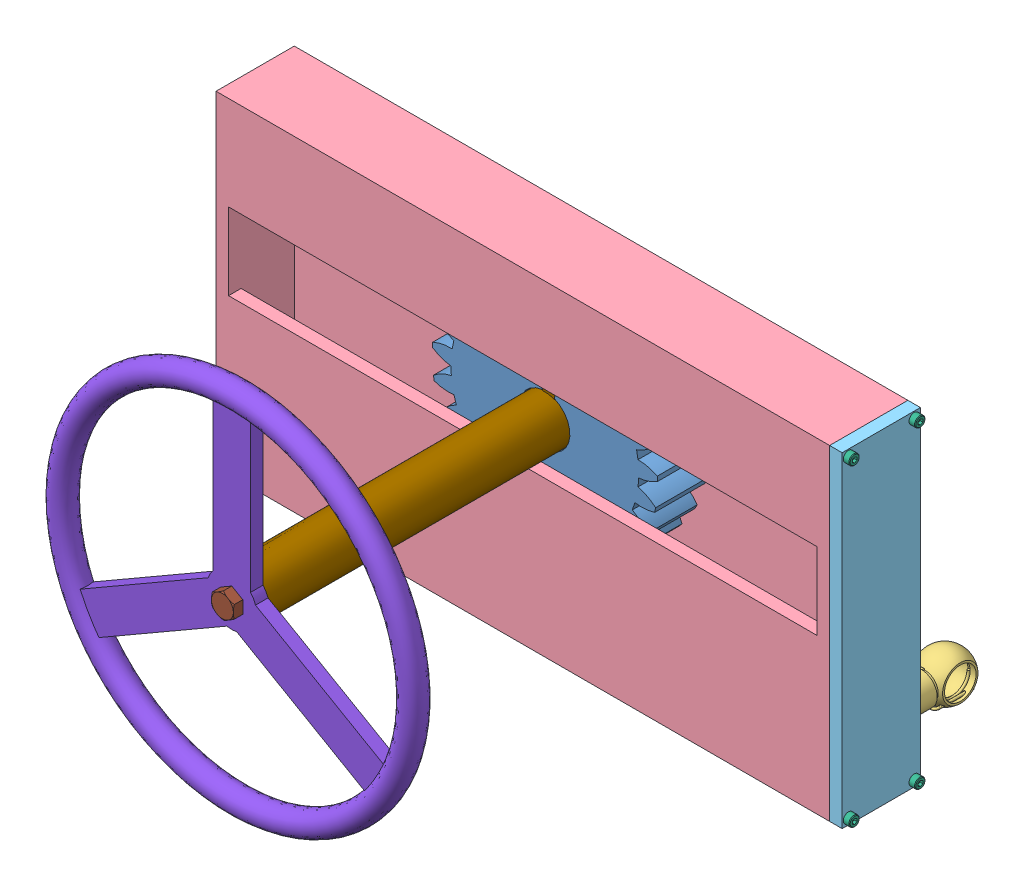
SolidWorks assembly STA1, configuration Default. Lengths in mm.
Overall size (320.68 259.28 240.21).
16 component instances, 11 part files, 39 mates.
Components (placement in the parent):
- STP10-3: STP10 [Default] at origin size (304.8 155.79 25.4)
  - spur gear_ai-4: spur gear_ai [Inch - Spur gear 6DP 25T 20PA 1FW ---S25N3.0H2.0L1.0S1] x (0 0 1) z (-0.989908 0.141715 0) size (25.4 113.98 114.2)
  - rack spur rectangular_ai-2: rack spur rectangular_ai [Inch - Rack-spur - rectangular 6DP 20PA 1FW 1.5PH 12L---SAll] at (-154.037 -91.44 25.4) size (304.8 42.33 25.4)
- STP01-11: STP01 [Default] at (138.063 -75.0375 -39.3517) x (0 1 0) z (0 0 -1) size (23.88 20.07 47.75)
- STP03-3: STP03 [Default] at (150.763 -97.79 31.75) x (0 0 -1) z (1 0 0) size (39.69 165.1 311.15)
- STP04-3: STP04 [Default] at (150.763 -97.79 -7.9375) x (0 0 1) z (-1 0 0) size (39.69 165.1 6.59)
- socket head cap screw_ai-1: socket head cap screw_ai [HX-SHCS 0.125-40x0.5x0.5-N] at (160.288 64.135 28.575) x (-1 0 0) z (0 0.866025 0.5) size (15.88 5.21 5.21)
- socket head cap screw_ai-2: socket head cap screw_ai [HX-SHCS 0.125-40x0.5x0.5-N] at (160.288 64.135 -4.7625) x (-1 0 0) z (0 0.866025 0.5) size (15.88 5.21 5.21)
- socket head cap screw_ai-4: socket head cap screw_ai [HX-SHCS 0.125-40x0.5x0.5-N] at (160.288 -94.615 28.575) x (-1 0 0) z (0 0.866025 0.5) size (15.88 5.21 5.21)
- socket head cap screw_ai-7: socket head cap screw_ai [HX-SHCS 0.125-40x0.5x0.5-N] at (160.288 -94.615 -4.7625) x (-1 0 0) z (0 0.866025 0.5) size (15.88 5.21 5.21)
- STP01-10: STP01 [Default] at (-141.337 -75.0375 -39.3517) x (0 -1 0) z (0 0 -1) size (23.88 20.07 47.75)
- STP05-2: STP05 [Default] at (-154.037 -58.6317 0) x (1 0 0) z (0 0 -1) size (304.8 32.77 26.99)
- STP06-1: STP06 [Default] at (-0.0036 -0.0251 180.975) x (0.5 -0.866025 0) z (0 0 1) size (189.81 189.81 12.01)
- STP07-1: STP07 [Default] at (-0.0036 -0.0251 -33.528) x (-0.141715 -0.989908 0) z (0 0 1) size (28 24.77 211.33)
- FWP4-1: FWP4 [Default] at (-20.7057 3.2593 -20.828) x (0 0 1) z (0.989908 -0.141715 0) size (12.7 12.7 39.95)
- hex bolt_ai-1: hex bolt_ai [HBOLT 0.2500-20x0.75x0.75-N] at (-0.0036 -0.0251 188.9252) x (0 0 -1) z (0.5 0.866025 0) size (23.83 12.85 11.13)
Mates (geometry in assembly coordinates):
- Coincident39: coincident: line of STP03-3 through (150.763 67.31 -7.9375) axis (0 0 1); line of STP04-3 through (150.763 67.31 31.75) axis (0 0 -1)
- Coincident40: coincident: line of STP03-3 through (-160.387 67.31 -7.9375) axis (1 0 0); line of STP04-3 through (157.113 67.31 -7.9375) axis (-1 0 0)
- Concentric211: concentric: cylinder of STP04-3 through (157.113 64.135 28.575) axis (-1 0 0) radius 1.2891; cylinder of socket head cap screw_ai-1 through (192.038 64.135 28.575) axis (1 0 0) radius 2.6035
- Coincident421: coincident: plane of STP04-3 through (157.113 -97.79 -7.9375) normal (1 0 0); plane of socket head cap screw_ai-1 through (157.113 62.8332 30.8297) normal (-1 0 0)
- Concentric221: concentric: cylinder of STP04-3 through (157.113 64.135 -4.7625) axis (-1 0 0) radius 1.2891; cylinder of socket head cap screw_ai-2 through (192.038 64.135 -4.7625) axis (1 0 0) radius 2.6035
- Coincident431: coincident: plane of STP04-3 through (157.113 -97.79 -7.9375) normal (1 0 0); plane of socket head cap screw_ai-2 through (157.113 62.8332 -2.5078) normal (-1 0 0)
- Concentric241: concentric: cylinder of STP04-3 through (157.113 -94.615 28.575) axis (-1 0 0) radius 1.2891; cylinder of socket head cap screw_ai-4 through (192.038 -94.615 28.575) axis (1 0 0) radius 2.6035
- Coincident451: coincident: plane of STP04-3 through (157.113 -97.79 -7.9375) normal (1 0 0); plane of socket head cap screw_ai-4 through (157.113 -95.9167 30.8297) normal (-1 0 0)
- Concentric261: concentric: cylinder of STP04-3 through (157.113 -94.615 -4.7625) axis (-1 0 0) radius 1.2891; cylinder of socket head cap screw_ai-7 through (192.038 -94.615 -4.7625) axis (1 0 0) radius 2.6035
- Coincident471: coincident: plane of STP04-3 through (157.113 -97.79 -7.9375) normal (1 0 0); plane of socket head cap screw_ai-7 through (157.113 -95.9167 -2.5078) normal (-1 0 0)
- Coincident476: coincident: point of STP10-3/rack spur rectangular_ai-2; point of STP05-2
- Coincident482: coincident: line of STP10-3/rack spur rectangular_ai-2 through (32.8083 -154.037 -58.6317) axis (0 0 -1); line of STP05-2 through (-154.037 -91.3977 0) axis (0 1 0)
- Parallel1: parallel: line of STP10-3 through (254 127 -91.44) axis (0 -1 0); line of STP05-2 through (304.8 150.763 -91.3977) axis (0 -1 0)
- Coincident487: coincident: plane of STP10-3/rack spur rectangular_ai-2 through (-154.037 -91.44 0) normal (-1 0 0); plane of STP03-3 through (-154.037 -97.79 31.75) normal (1 0 0)
- Coincident488: coincident: line of STP10-3/rack spur rectangular_ai-2 through (150.763 -91.44 0) axis (0 0 1); line of STP03-3 through (150.763 -91.44 25.4) axis (0 0 -1)
- Coincident489: coincident: line of STP10-3/rack spur rectangular_ai-2 through (-154.037 -91.44 25.4) axis (1 0 0); line of STP03-3 through (-154.037 -91.44 25.4) axis (1 0 0)
- Concentric262: concentric: circle of STP01-11; circle of STP05-2
- Coincident490: coincident: cone of STP01-11 through (138.063 -75.0375 -26.6517) axis (0 0 -1); circle of STP05-2
- Parallel2: parallel: plane of STP01-11 through (145.937 -87.7375 -39.3517) normal (1 0 0); plane of STP04-3 through (157.113 -97.79 -7.9375) normal (1 0 0)
- Concentric263: concentric: circle of STP01-10; circle of STP05-2
- Coincident492: coincident: cone of STP01-10 through (-141.337 -75.0375 -26.6517) axis (0 0 -1); circle of STP05-2
- Angle2: planar angle = 3.141593 rad: plane of STP01-10 through (-149.211 -62.3375 -39.3517) normal (-1 0 0); plane of STP03-3 through (-160.387 -97.79 31.75) normal (-1 0 0)
- Coincident500: coincident: plane of STP10-3/spur gear_ai-4 through (0 0 25.4) normal (0 0 1); plane of STP07-1 through (-0.0036 -0.0251 25.4) normal (0 0 1)
- Coincident504: coincident: plane of STP07-1 through (-0.0036 -0.0251 165.1) normal (0 0 1); circle of hex bolt_ai-1
- Tangent5: tangent: cylinder of STP07-1 through (-0.0036 -0.0251 25.4) axis (0 0 -1) radius 12.3825; cylinder of FWP4-1 through (13.8668 -1.6901 -14.478) axis (0 0 -1) radius 1.5875
- Parallel5: parallel: plane of STP03-3 through (-160.387 -97.79 -7.9375) normal (0 0 -1); plane of socket head cap screw_ai-2 through (158.8402 63.4458 -3.5687) normal (0 0 -1)
- Parallel6: parallel: plane of STP03-3 through (-160.387 -97.79 -7.9375) normal (0 0 -1); plane of socket head cap screw_ai-1 through (158.8402 63.4458 29.7688) normal (0 0 -1)
- Parallel7: parallel: plane of STP03-3 through (-160.387 -97.79 -7.9375) normal (0 0 -1); plane of socket head cap screw_ai-7 through (158.8402 -95.3042 -3.5687) normal (0 0 -1)
- Parallel8: parallel: plane of STP03-3 through (-160.387 -97.79 -7.9375) normal (0 0 -1); plane of socket head cap screw_ai-4 through (158.8402 -95.3042 29.7688) normal (0 0 -1)
- Parallel9: parallel: plane of STP04-3 through (157.113 -97.79 -7.9375) normal (1 0 0); plane of hex bolt_ai-1 through (5.559 -3.2367 184.15) normal (1 0 0)
- Parallel10: parallel: plane of STP04-3 through (157.113 -97.79 -7.9375) normal (1 0 0); plane of STP06-1 through (9.5214 -0.0251 184.15) normal (1 0 0)
- Concentric264: concentric: cylinder of STP06-1 through (-0.0036 -0.0251 184.15) axis (0 0 -1) radius 3.175; cylinder of hex bolt_ai-1 through (-0.0036 -0.0251 188.9252) axis (0 0 1) radius 3.175
- Concentric265: concentric: circle of STP07-1; cylinder of hex bolt_ai-1 through (-0.0036 -0.0251 188.9252) axis (0 0 1) radius 3.175
- Coincident505: coincident: line of STP10-3/spur gear_ai-4 through (4.8856 11.7227 25.4) axis (0.141715 0.989908 0); line of STP07-1 through (4.8355 11.3726 25.4) axis (0.141715 0.989908 0)
- Coincident506: coincident: line of STP06-1 through (9.5214 8.3751 177.8) axis (0 1 0); plane of STP07-1 through (-0.0036 -0.0251 177.8) normal (0 0 1)
- Concentric267: concentric: cylinder of STP07-1 through (-12.2161 2.0439 -20.828) axis (0.989908 -0.141715 0) radius 3.175; cylinder of FWP4-1 through (17.0098 -2.14 -20.828) axis (-0.989908 0.141715 0) radius 3.175
- Tangent8: tangent: cylinder of STP07-1 through (-0.0036 -0.0251 25.4) axis (0 0 -1) radius 12.3825; cylinder of FWP4-1 through (13.8668 -1.6901 -14.478) axis (0 0 -1) radius 1.5875
- Parallel12: parallel: plane of STP07-1 through (-0.0036 -0.0251 -33.528) normal (0 0 -1); plane of FWP4-1 through (13.8668 -1.6901 -27.178) normal (0 0 -1)
- Coincident508: coincident: line of STP10-3/spur gear_ai-4 through (5.3531 14.9883 25.4) axis (-0.989908 0.141715 0); line of STP07-1 through (5.3531 14.9883 25.4) axis (-0.989908 0.141715 0)
